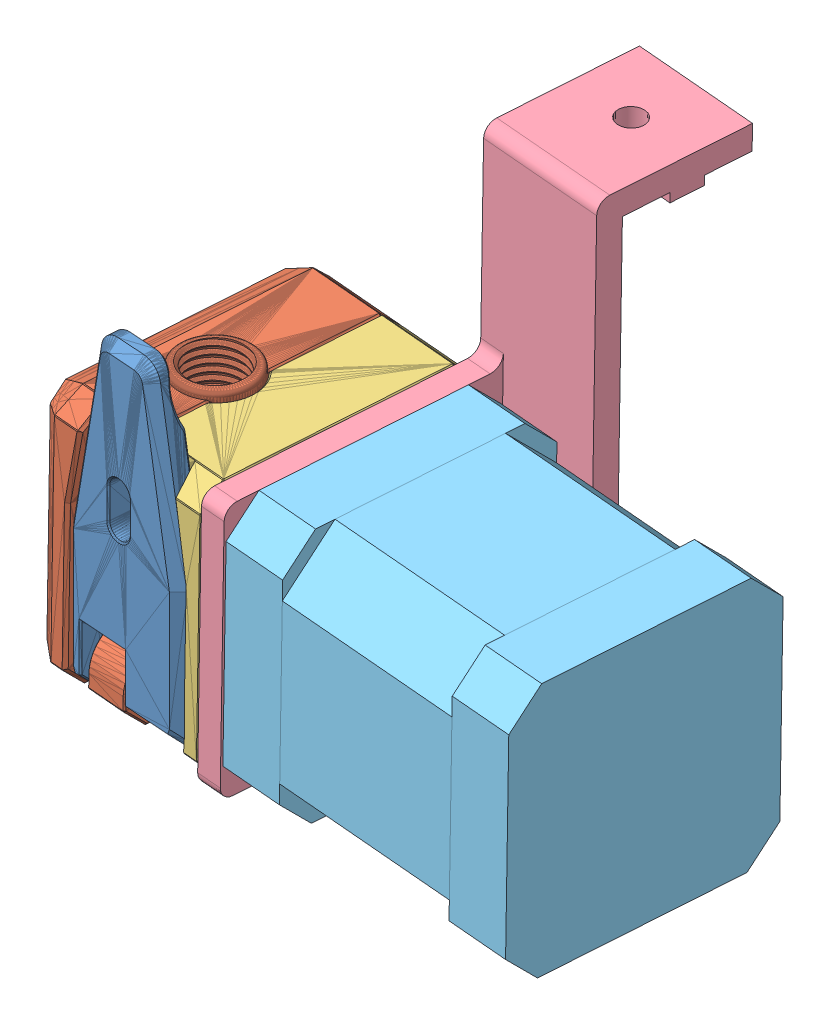
SolidWorks assembly Bondtech_extruder, configuration Default. Lengths in mm.
Overall size (86.45 73.82 52.55).
5 component instances, 5 part files, 12 mates.
Components (placement in the parent):
- Bondtech_arm-1: Bondtech_arm [Default] at (594.2842 355.0346 -89.1644) x (-0.000002 1 0.000028) z (0.069756 0.000028 -0.997564) size (55 20 18)
- bondtech_bot-1: bondtech_bot [Default] at (654.0473 445.909 5.5666) x (0.068216 0.000091 -0.997671) z (0.997515 -0.017664 0.068204) size (42.5 43.5 19)
- bondtech_top-1: bondtech_top [Default] at (698.1084 430.1483 -217.7356) x (-0.068216 -0.000091 0.997671) z (-0.997515 0.017664 -0.068204) size (42.5 42.5 13)
- motor_mount-1: motor_mount [Default] at (692.9645 491.4813 -126.6187) x (0.068216 0.000091 -0.997671) z (0.997515 -0.017664 0.068204) size (49.28 72.88 20)
- DummyNema17.step-1-1: DummyNema17.step-1 [Default] at (746.8064 490.5274 -122.5865) x (0.017617 0.999844 0.001296) z (-0.068216 -0.000091 0.997671) size (42.3 72 42.3)
Mates (geometry in assembly coordinates):
- Coincident103: coincident: plane of Bondtech_arm-1 through (589.8606 399.4386 -25.9036) normal (0.057141 -0.573577 -0.817156); line of bondtech_top-1 through (690.256 498.1909 -88.1993) axis (-0.053558 -0.819076 0.57118)
- Coincident104: coincident aligned: plane of Bondtech_arm-1 through (595.515 356.5785 -106.7658) normal (0.069491 0.087167 -0.993767); plane of bondtech_top-1 through (689.504 419.3552 -94.687) normal (0.069491 0.087167 -0.993767)
- Coincident109: coincident: point of Bondtech_arm-1; plane of bondtech_top-1 through (695.6146 430.1925 -217.9061) normal (-0.997515 0.017664 -0.068204)
- Width76: width anti-aligned: plane of bondtech_top-1 through (699.9362 533.883 -217.6012) normal (0.017617 0.999844 0.001296); plane of bondtech_top-1 through (699.1874 491.3896 -217.6562) normal (-0.017617 -0.999844 -0.001296); plane of bondtech_bot-1 through (654.8573 491.8813 5.6262) normal (-0.017617 -0.999844 -0.001296); plane of bondtech_bot-1 through (655.606 534.3747 5.6813) normal (0.017617 0.999844 0.001296)
- Width77: width anti-aligned: plane of bondtech_top-1 through (691.8496 430.14 -126.1993) normal (0.068216 0.000091 -0.997671); plane of bondtech_top-1 through (688.9504 430.1361 -83.7983) normal (-0.068216 -0.000091 0.997671); plane of bondtech_bot-1 through (660.2915 445.9173 -85.7564) normal (-0.068216 -0.000091 0.997671); plane of bondtech_bot-1 through (663.1907 445.9212 -128.1574) normal (0.068216 0.000091 -0.997671)
- Coincident100: coincident anti-aligned: plane of bondtech_bot-1 through (670.0075 445.6264 6.6579) normal (0.997515 -0.017664 0.068204); plane of bondtech_top-1 through (685.1407 430.3779 -218.6223) normal (-0.997515 0.017664 -0.068204)
- Coincident110: coincident anti-aligned: plane of bondtech_top-1 through (698.1084 430.1483 -217.7356) normal (0.997515 -0.017664 0.068204); plane of motor_mount-1 through (692.9645 491.4813 -126.6187) normal (-0.997515 0.017664 -0.068204)
- Width78: width anti-aligned: plane of motor_mount-1 through (713.1877 491.1284 -129.2453) normal (-0.017617 -0.999844 -0.001296); plane of bondtech_top-1 through (697.6998 533.704 -126.291) normal (0.017617 0.999844 0.001296); plane of motor_mount-1 through (699.9362 533.883 -217.6012) normal (0.017617 0.999844 0.001296); plane of bondtech_top-1 through (699.1874 491.3896 -217.6562) normal (-0.017617 -0.999844 -0.001296)
- Coincident111: coincident aligned: plane of bondtech_top-1 through (688.9504 430.1361 -83.7983) normal (-0.068216 -0.000091 0.997671); plane of motor_mount-1 through (694.0213 491.4067 -83.446) normal (-0.068216 -0.000091 0.997671)
- Concentric1: concentric anti-aligned: cylinder of motor_mount-1 through (695.0762 528.0516 -89.3845) axis (-0.997515 0.017664 -0.068204) radius 1.6; cylinder of DummyNema17.step-1-1 through (695.0762 528.0516 -89.3845) axis (0.997515 -0.017664 0.068204) radius 1.5
- Parallel1: parallel aligned: plane of motor_mount-1 through (694.0213 491.4067 -83.446) normal (-0.068216 -0.000091 0.997671); plane of DummyNema17.step-1-1 through (704.0203 491.2301 -83.1132) normal (-0.068216 -0.000091 0.997671)
- Coincident113: coincident anti-aligned: plane of motor_mount-1 through (696.9546 491.4106 -126.3458) normal (0.997515 -0.017664 0.068204); plane of DummyNema17.step-1-1 through (695.8605 512.5554 -104.8685) normal (-0.997515 0.017664 -0.068204)
